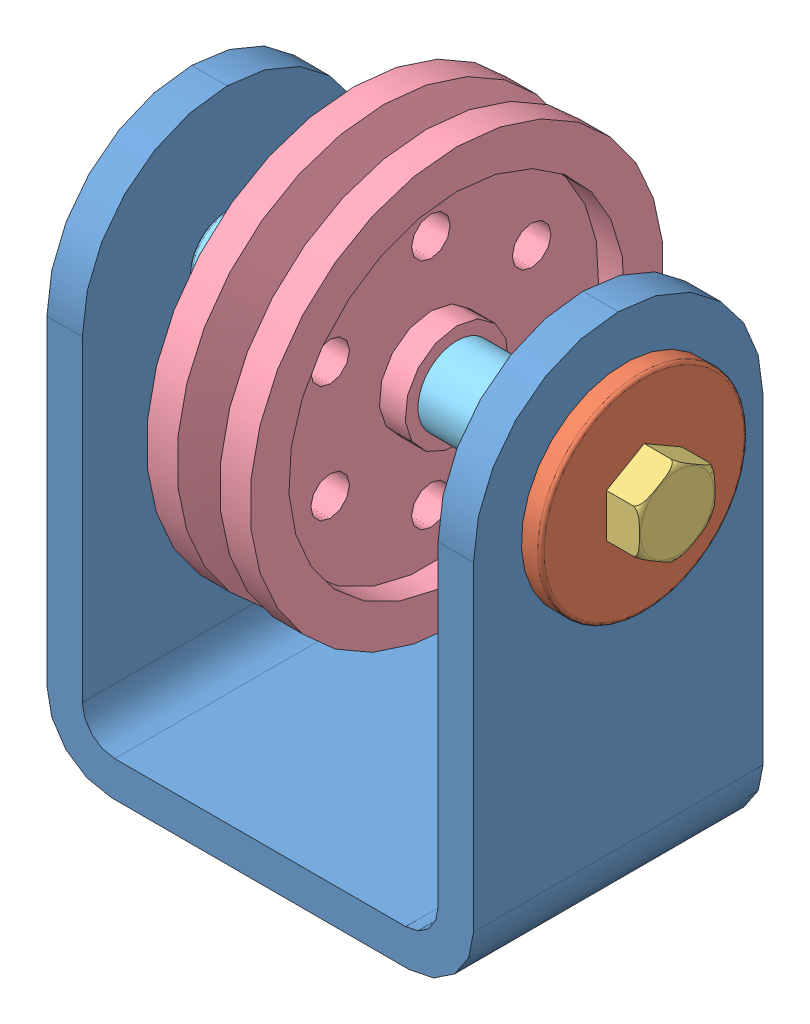
SolidWorks assembly IDLER ASSEMBLY v1, configuration Default. Lengths in mm.
Overall size (135.95 145.29 101.6).
7 component instances, 5 part files, 10 mates.
Components (placement in the parent):
- U-BRACKET v1-1: U-BRACKET v1 [Default] at origin size (104.77 130.05 71.12)
- BEARING v1-1: BEARING v1 [Default] at (-58.7502 94.488 0) x (0 -0.837152 0.546971) z (0 0.546971 0.837152) size (50.8 11.13 50.8)
- BOLT-1: BOLT [Default] at (-58.7502 94.488 0) x (0 0 -1) z (0 1 0) size (20.81 34.62 23.67)
- IDLER v2-1: IDLER v2 [Default] at (0 94.488 0) x (0 0 1) z (0 1 0) size (101.6 25.4 101.6)
- INDEX SHAFT v6-1: INDEX SHAFT v6 [Default] at (0 94.488 0) x (0 -0.798488 0.602011) z (0 0.602011 0.798488) size (19.05 87.35 19.05)
- BEARING v1-2: BEARING v1 [Default] at (58.7502 94.488 0) x (0 -0.837152 0.546971) z (0 -0.546971 -0.837152) size (50.8 11.13 50.8)
- BOLT-2: BOLT [Default] at (58.7502 94.488 0) x (0 0 -1) z (0 -1 0) size (20.81 34.62 23.67)
Mates (geometry in assembly coordinates):
- Concentric6: concentric aligned: cylinder of IDLER v2-1 through (0 94.488 0) axis (1 0 0) radius 9.525; cylinder of INDEX SHAFT v6-1 through (543.0052 94.488 0) axis (1 0 0) radius 9.525
- Coincident6: coincident aligned: plane of IDLER v2-1; plane of INDEX SHAFT v6-1
- Coincident7: coincident aligned: plane of INDEX SHAFT v6-1; plane of assembly through (0 0 0) normal (1 0 0)
- Concentric7: concentric aligned: cylinder of U-BRACKET v1-1 through (52.3875 94.488 0) axis (1 0 0) radius 7.1501; cylinder of INDEX SHAFT v6-1 through (543.0052 94.488 0) axis (1 0 0) radius 9.525
- Concentric8: concentric anti-aligned: cylinder of BEARING v1-1 through (-58.7502 94.488 0) axis (1 0 0) radius 6.7469; cylinder of BOLT-1 through (-33.3502 94.488 0) axis (-1 0 0) radius 6.35
- Coincident8: coincident anti-aligned: plane of BEARING v1-1 through (-58.7502 73.8888 13.4589) normal (-1 0 0); plane of BOLT-1 through (-58.7502 83.7905 0) normal (1 0 0)
- Concentric9: concentric aligned: cylinder of BOLT-1 through (-33.3502 94.488 0) axis (-1 0 0) radius 6.35; cylinder of INDEX SHAFT v6-1 through (-43.6753 94.488 0) axis (-1 0 0) radius 5.3581
- Coincident9: coincident anti-aligned: plane of U-BRACKET v1-1 through (-47.625 101.6381 0) normal (-1 0 0); plane of BEARING v1-1 through (-47.625 94.488 0) normal (1 0 0)
- Perpendicular1: perpendicular: plane of BOLT-1; plane of assembly through (0 0 0) normal (0 1 0)
- Parallel3: parallel aligned: plane of IDLER v2-1 through (0 94.488 0) normal (0 1 0); plane of assembly through (0 0 0) normal (0 1 0)
